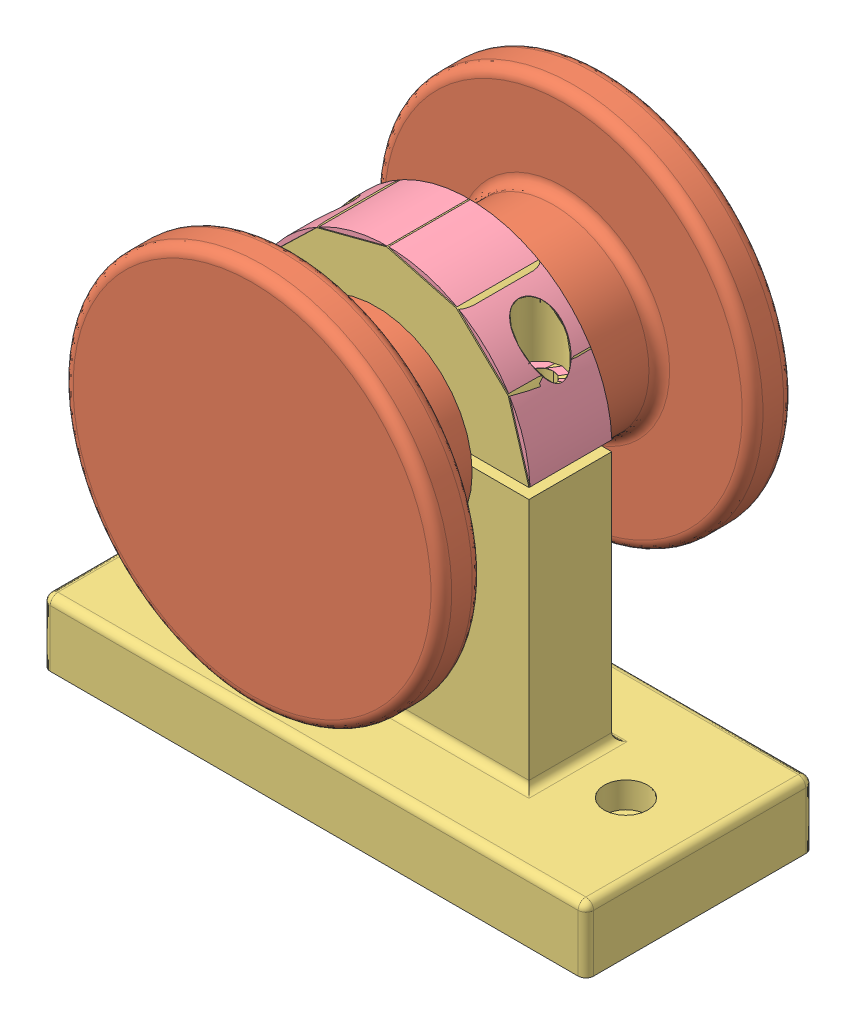
SolidWorks assembly FinalcollarAssembly, configuration Default. Lengths in mm.
Overall size (105 98.58 68.14).
5 component instances, 4 part files, 9 mates.
Components (placement in the parent):
- LCFD-1: LCFD [Default] at (-21.6889 13.2577 150.205) x (0 -1 0) z (0 0 1) size (32.7 25.4 22.65)
- plate_attachment-1: plate_attachment [Default] at (-21.6889 13.2577 158.46) x (0 0 -1) z (1 0 0) size (26 73.15 73.15)
- plate_attachment-2: plate_attachment [Default] at (-21.6889 13.2577 158.1) x (0 0 1) z (-1 0 0) size (26 73.15 73.15)
- bottom_collar2-1: bottom_collar2 [Default] at (-21.6889 -48.7423 158.355) size (105 89.54 44)
- top_collar2-1: top_collar2 [Default] at (-21.6889 -48.7423 158.355) size (55.04 26.54 15.8)
Mates (geometry in assembly coordinates):
- Coincident4: coincident anti-aligned: plane of LCFD-1 through (-21.6889 13.2577 150.205) normal (0 0 -1); plane of plate_attachment-1 through (-21.6889 13.2577 150.205) normal (0 0 1)
- Concentric3: concentric anti-aligned: cylinder of LCFD-1 through (-21.6889 13.2577 143.855) axis (0 0 1) radius 2.5; cone of plate_attachment-1 through (-21.6889 13.2577 150.205) axis (0 0 -1)
- Concentric4: concentric aligned: cylinder of LCFD-1 through (-21.6889 13.2577 143.855) axis (0 0 1) radius 2.5; cone of plate_attachment-2 through (-21.6889 13.2577 166.355) axis (0 0 1)
- Concentric5: concentric aligned: cylinder of LCFD-1 through (-21.6889 13.2577 163.505) axis (0 0 -1) radius 12.7; cylinder of bottom_collar2-1 through (-21.6889 13.2577 166.355) axis (0 0 -1) radius 13.25
- Concentric6: concentric anti-aligned: cylinder of LCFD-1 through (-21.6889 -6.7423 158.355) axis (0 1 0) radius 3.175; cylinder of bottom_collar2-1 through (-21.6889 12.2577 158.355) axis (0 -1 0) radius 3.325
- Coincident6: coincident anti-aligned: plane of plate_attachment-2 through (-21.6889 13.2577 166.355) normal (0 0 -1); plane of bottom_collar2-1 through (-21.6889 13.2577 166.355) normal (0 0 1)
- Concentric7: concentric aligned: cylinder of bottom_collar2-1 through (-1.3334 -0.2673 157.005) axis (0 1 0) radius 3.7138; cylinder of top_collar2-1 through (-6.9986 24.9577 157.3688) axis (0 1 0) radius 2.5
- Concentric8: concentric aligned: cylinder of bottom_collar2-1 through (-42.0443 -0.2673 157.005) axis (0 1 0) radius 3.7138; cylinder of top_collar2-1 through (-42.0443 13.2577 157.005) axis (0 1 0) radius 2.5
- Concentric9: concentric aligned: cylinder of LCFD-1 through (-21.6889 13.2577 163.505) axis (0 0 -1) radius 12.7; cylinder of top_collar2-1 through (-21.6889 13.2577 166.355) axis (0 0 -1) radius 13.25
